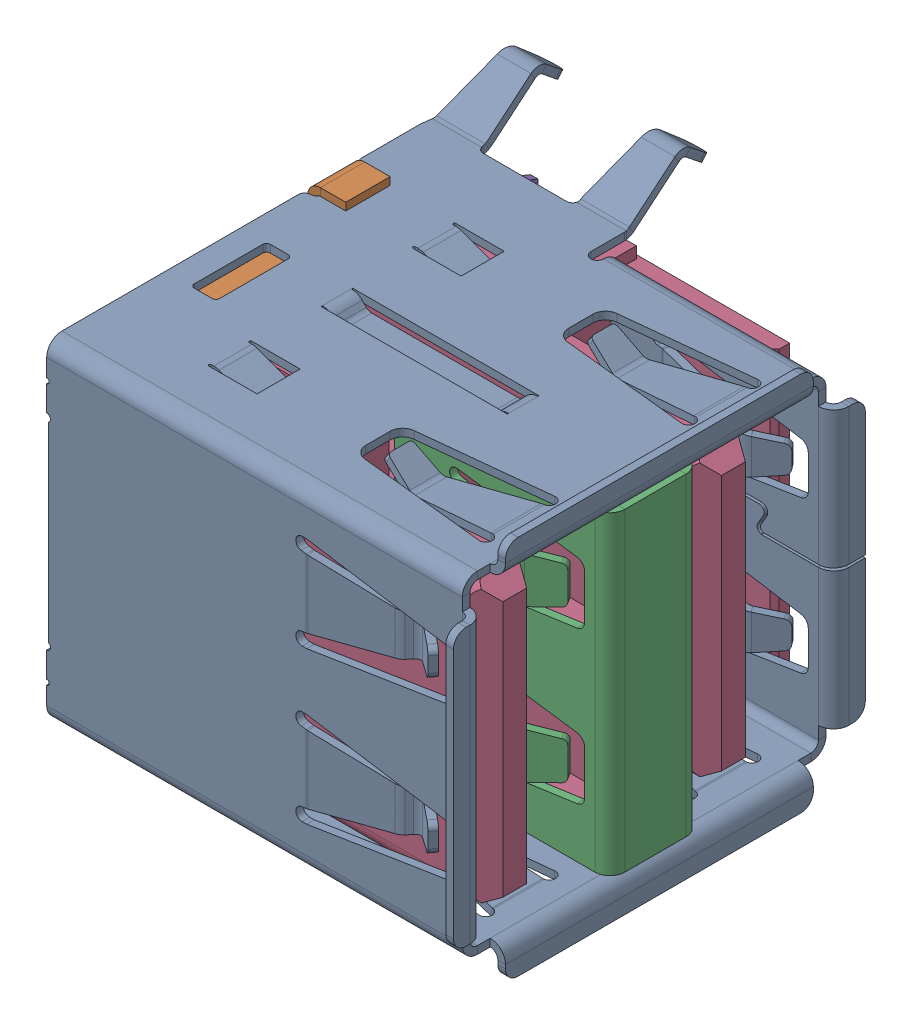
SolidWorks assembly USB-A-stack-1x2_1.stp, configuration Default. Lengths in mm.
Overall size (17 15.83 20.03).
15 component instances, 6 part files, 0 mates.
Components (placement in the parent):
- shell_2.stp-1: shell_2.stp [Default] at origin size (17 15.83 20.03)
  - outer.stp-1: outer.stp [Default] at origin size (17 15.83 20.03)
  - back_shell.stp-1: back_shell.stp [Default] at origin size (2.8 13.7 13.5)
  - mid_cover.stp-1: mid_cover.stp [Default] at origin size (8.5 12.4 5.09)
- Component4_1.stp-1: Component4_1.stp [Default] at origin size (16.25 12.4 15.02)
  - Component5.stp-1: Component5.stp [Default] at origin size (16.25 12.4 15.02)
- leads_2.stp-1: leads_2.stp [Default] at origin size (14.29 8.54 16.6)
  - top_lead.stp-1: top_lead.stp [Default] at origin size (14.29 1.54 16.6)
  - top_lead.stp-2: top_lead.stp [Default] at (0 -2.5 0) size (14.29 1.54 16.6)
  - top_lead.stp-3: top_lead.stp [Default] at (0 -7 0) size (14.29 1.54 16.6)
  - top_lead.stp-4: top_lead.stp [Default] at (0 -4.5 0) size (14.29 1.54 16.6)
  - bottom_lead.stp-1: bottom_lead.stp [Default] at origin size (11.67 1.54 7.97)
  - bottom_lead.stp-2: bottom_lead.stp [Default] at (0 -7 0) size (11.67 1.54 7.97)
  - bottom_lead.stp-3: bottom_lead.stp [Default] at (0 -2.5 0) size (11.67 1.54 7.97)
  - bottom_lead.stp-4: bottom_lead.stp [Default] at (0 -4.5 0) size (11.67 1.54 7.97)
